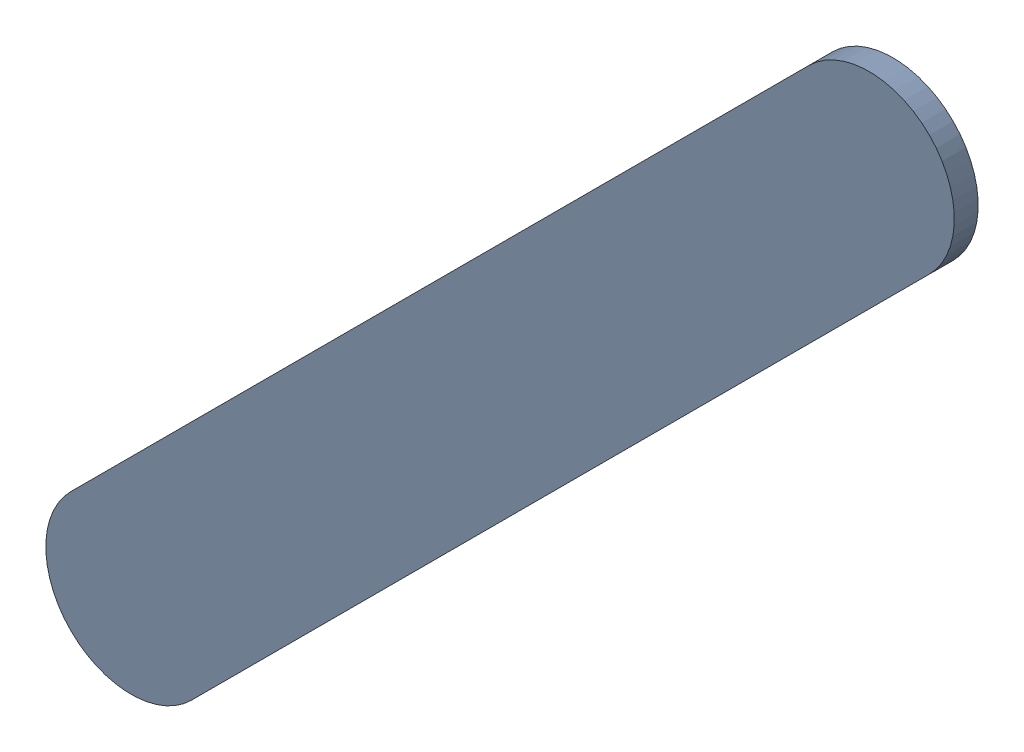
SolidWorks assembly Track (7.2mm,49.6mm)(8.3mm,50.7mm) on Bottom Layer, configuration Predeterminado. Lengths in mm.
Overall size (1.35 1.35 0.04).
2 component instances, 1 part files, 0 mates.
Components (placement in the parent):
- Track (7.2mm,49.6mm)(8.3mm,50.7mm) on Bottom Layer-1-1: Track (7.2mm,49.6mm)(8.3mm,50.7mm) on Bottom Layer-1 [Predeterminado] at (-68.317 -44.187 -0.4013) size (1.35 1.35 0.04)
  - Track (7.2mm,49.6mm)(8.3mm,50.7mm) on Bottom Layer-Part-1-1: Track (7.2mm,49.6mm)(8.3mm,50.7mm) on Bottom Layer-Part-1 [Predeterminado] at origin size (1.35 1.35 0.04)
